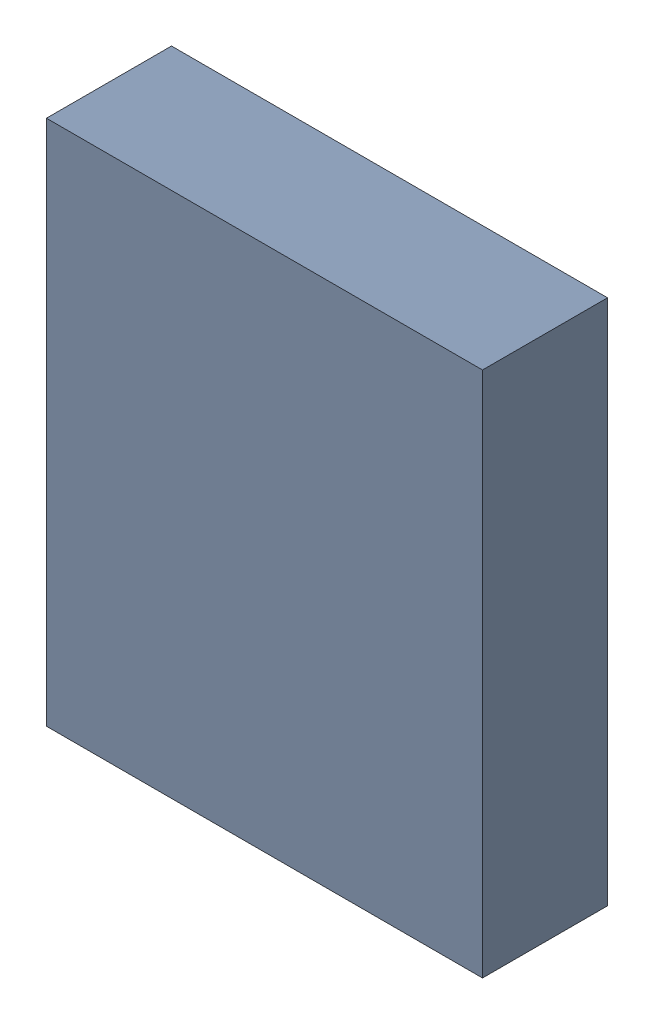
SolidWorks assembly U9, configuration Default. Lengths in mm.
Overall size (2.65 3.2 0.78).
4 component instances, 2 part files, 0 mates.
Components (placement in the parent):
- 676625696-1: 676625696 [Default] at (16.575 54.05 -1.2715) size (2.65 3.2 0.76)
  - Extruded (6)-1: Extruded (6) [Default] at origin size (2.65 3.2 0.76)
- 756979608-1: 756979608 [Default] at (17.6 52.85 -0.7115) x (0 -1 0) z (0 0 -1) size (0.2 0.2 0.58)
  - Cylinder-1: Cylinder [Default] at origin size (0.2 0.2 0.58)
